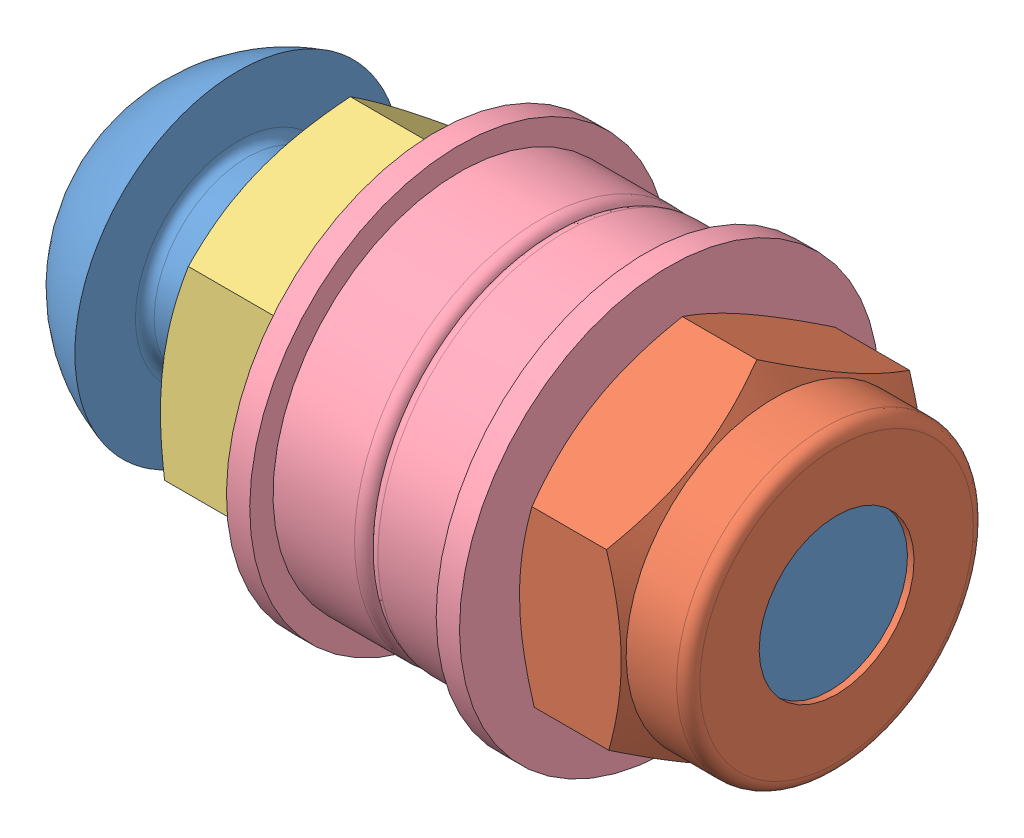
SolidWorks assembly ASM Roller Bolt, configuration Standard. Lengths in mm.
Overall size (30.9 25.4 25.4).
5 component instances, 4 part files, 7 mates.
Components (placement in the parent):
- M8X25 Pan Head Screw-1: M8X25 Pan Head Screw [Standard] at origin size (30.62 14.79 14.79)
- M8 Self-locking nut-1: M8 Self-locking nut [Standard] at (27.7325 0 0) x (0 0.488663 0.872473) z (1 0 0) size (15.01 13 7.18)
- M8 nut-1: M8 nut [Standard] at (7.4 0 0) x (0 0.613039 0.790053) z (-1 0 0) size (15.01 13 5.5)
- F688 pillow-1: F688 pillow [Standard] at (22.9 0 0) x (0 0.424513 0.905422) z (0 -0.905422 0.424513) size (18 5 18)
- F688 pillow-2: F688 pillow [Standard] at (12.9 0 0) x (0 0.751639 -0.659574) z (0 -0.659574 -0.751639) size (18 5 18)
Mates (geometry in assembly coordinates):
- Konzentrisch35: concentric aligned: cylinder of M8X25 Pan Head Screw-1 through (14.4 0 0) axis (-1 0 0) radius 4; cylinder of M8 nut-1 through (14.2 0 0) axis (-1 0 0) radius 3.3235
- Konzentrisch36: concentric aligned: cylinder of M8X25 Pan Head Screw-1 through (14.4 0 0) axis (-1 0 0) radius 4; cylinder of F688 pillow-2 through (17.9 0 0) axis (-1 0 0) radius 4
- Konzentrisch37: concentric anti-aligned: cylinder of M8X25 Pan Head Screw-1 through (14.4 0 0) axis (-1 0 0) radius 4; cylinder of F688 pillow-1 through (17.9 0 0) axis (1 0 0) radius 4
- Konzentrisch38: concentric anti-aligned: cylinder of M8X25 Pan Head Screw-1 through (14.4 0 0) axis (-1 0 0) radius 4; cylinder of M8 Self-locking nut-1 through (22.5825 0 0) axis (1 0 0) radius 3.3235
- Deckungsgleich34: coincident anti-aligned: plane of M8 Self-locking nut-1 through (22.9 0.1695 -12.9989) normal (-1 0 0); plane of F688 pillow-1 through (22.9 0 0) normal (1 0 0)
- Deckungsgleich32: coincident anti-aligned: plane of M8 nut-1 through (12.9 -6.1931 -10.6321) normal (1 0 0); plane of F688 pillow-2 through (12.9 0 0) normal (-1 0 0)
- Deckungsgleich33: coincident anti-aligned: plane of F688 pillow-1 through (17.9 0 0) normal (-1 0 0); plane of F688 pillow-2 through (17.9 0 0) normal (1 0 0)
